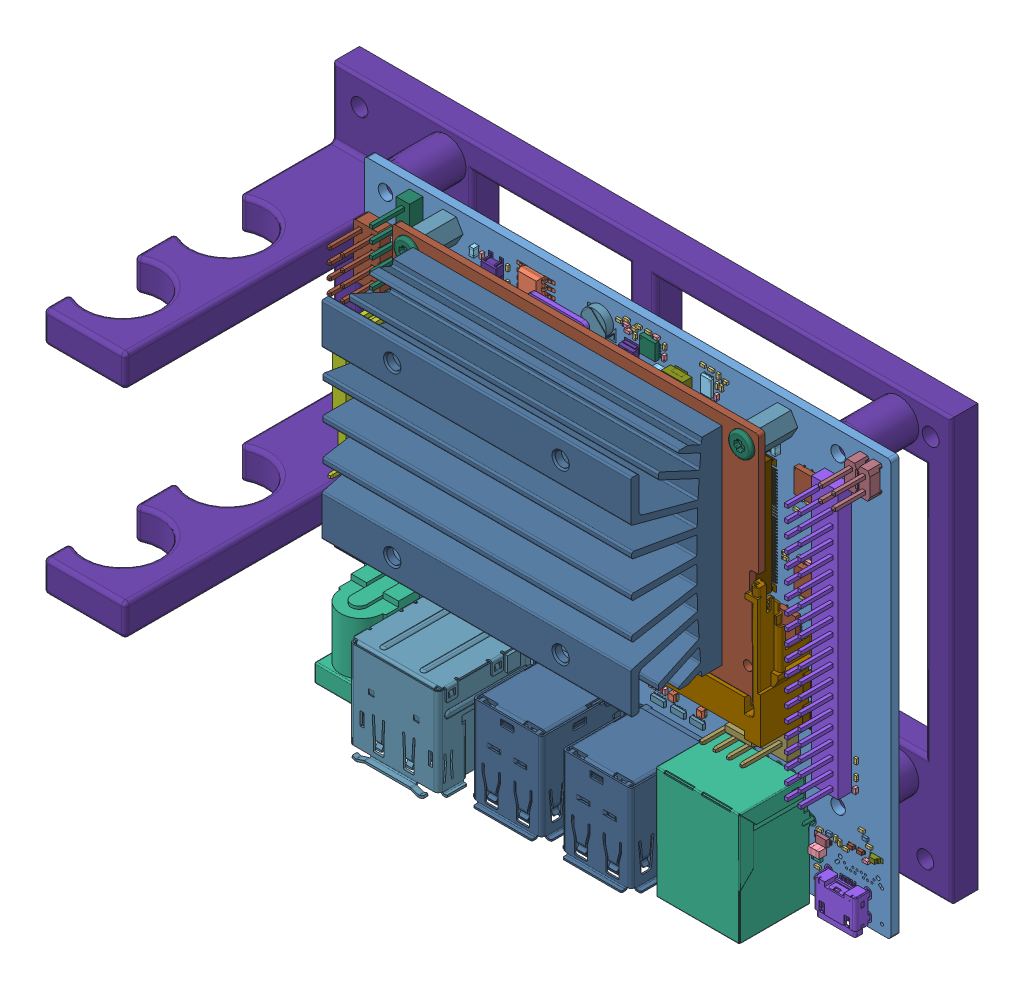
SolidWorks assembly FullJetsonMount, configuration Default. Lengths in mm.
Overall size (117.5 82.03 60).
402 component instances, 71 part files, 3 mates.
Components (placement in the parent):
- Jetson nano_fixed.step-1: Jetson nano_fixed.step [Default] at (-87.2795 66.2016 132.9895) size (100 81.03 30.51)
  - 142-13449-1000-A02_ASM.step-1: 142-13449-1000-A02_ASM.step [Default] at origin size (100 81.03 23.18)
    - 142-13449-1000-A02.step-1: 142-13449-1000-A02.step [Default] at origin size (100 79 1.57)
    - 315-1109-000_1.step-1: 315-1109-000_1.step [Default] at (5.6 4.9 1.575) x (-1 0 0) z (0 0 1) size (4.5 3.5 0.8)
    - 0402_H040.step-1: 0402_H040.step [Default] at (8 -0.825 1.575) size (1 0.5 0.4)
    - 0402_H060.step-1: 0402_H060.step [Default] at (1 5 1.575) x (0 -1 0) z (0 0 1) size (1 0.5 0.6)
    - 0402_H040.step-2: 0402_H040.step [Default] at (9.9 -0.3 1.575) size (1 0.5 0.4)
    - 0402_H040.step-3: 0402_H040.step [Default] at (8.296 51.194 1.575) x (-1 0 0) z (0 0 1) size (1 0.5 0.4)
    - 0402_H040.step-4: 0402_H040.step [Default] at (76.2 36.9 1.575) x (-1 0 0) z (0 0 1) size (1 0.5 0.4)
    - 0402_H040.step-5: 0402_H040.step [Default] at (37.8 2.87 1.575) x (0 -1 0) z (0 0 1) size (1 0.5 0.4)
    - 0402_H040.step-6: 0402_H040.step [Default] at (38.6 2.87 1.575) x (0 -1 0) z (0 0 1) size (1 0.5 0.4)
    - 0402_H060.step-2: 0402_H060.step [Default] at (14.2 7.7 1.575) x (0 -1 0) z (0 0 1) size (1 0.5 0.6)
    - 0402_H040.step-7: 0402_H040.step [Default] at (64 27.5 1.575) x (-1 0 0) z (0 0 1) size (1 0.5 0.4)
    - 0402_H060.step-3: 0402_H060.step [Default] at (18.6 43.15 1.575) x (-1 0 0) z (0 0 1) size (1 0.5 0.6)
    - 0402_H060.step-4: 0402_H060.step [Default] at (65.5 52.8 1.575) x (0 1 0) z (0 0 1) size (1 0.5 0.6)
    - 0402_H060.step-5: 0402_H060.step [Default] at (64 28.4 1.575) x (-1 0 0) z (0 0 1) size (1 0.5 0.6)
    - 0402_H040.step-8: 0402_H040.step [Default] at (60.95 25.85 1.575) size (1 0.5 0.4)
    - 0402_H060.step-6: 0402_H060.step [Default] at (17.3 7.7 1.575) x (0 -1 0) z (0 0 1) size (1 0.5 0.6)
    - 0402_H060.step-7: 0402_H060.step [Default] at (18.6 7.7 1.575) x (0 -1 0) z (0 0 1) size (1 0.5 0.6)
    - 0402_H060.step-8: 0402_H060.step [Default] at (12.9 7.7 1.575) x (0 -1 0) z (0 0 1) size (1 0.5 0.6)
    - 0402_H060.step-9: 0402_H060.step [Default] at (80.9 37.7 1.575) x (-1 0 0) z (0 0 1) size (1 0.5 0.6)
    - 0402_H040.step-9: 0402_H040.step [Default] at (79.5 31.3 1.575) size (1 0.5 0.4)
    - 0402_H040.step-10: 0402_H040.step [Default] at (81 31.3 1.575) x (-1 0 0) z (0 0 1) size (1 0.5 0.4)
    - 0402_H060.step-10: 0402_H060.step [Default] at (79.3 37.7 1.575) size (1 0.5 0.6)
    - 0402_H060.step-11: 0402_H060.step [Default] at (74.8 4.05 1.575) x (-1 0 0) z (0 0 1) size (1 0.5 0.6)
    - 0402_H040.step-11: 0402_H040.step [Default] at (65.675 6.15 1.575) x (0 -1 0) z (0 0 1) size (1 0.5 0.4)
    - 0402_H060.step-12: 0402_H060.step [Default] at (67.7 6.85 1.575) x (0 1 0) z (0 0 1) size (1 0.5 0.6)
    - 0402_H040.step-12: 0402_H040.step [Default] at (64.475 5.8 1.575) x (-1 0 0) z (0 0 1) size (1 0.5 0.4)
    - 0402_H040.step-13: 0402_H040.step [Default] at (67.725 5.325 1.575) x (0 1 0) z (0 0 1) size (1 0.5 0.4)
    - 0402_H060.step-13: 0402_H060.step [Default] at (46.1 59.45 1.575) size (1 0.5 0.6)
    - 0402_H040.step-14: 0402_H040.step [Default] at (44.65 59.45 1.575) size (1 0.5 0.4)
    - 0402_H040.step-15: 0402_H040.step [Default] at (46.1 60.25 1.575) size (1 0.5 0.4)
    - 0402_H060.step-14: 0402_H060.step [Default] at (53.35 57.7 1.575) x (0 -1 0) z (0 0 1) size (1 0.5 0.6)
    - 0402_H040.step-16: 0402_H040.step [Default] at (47.6 59.45 1.575) size (1 0.5 0.4)
    - 0402_H040.step-17: 0402_H040.step [Default] at (48.4 60.25 1.575) size (1 0.5 0.4)
    - 0402_H040.step-18: 0402_H040.step [Default] at (47.7 58.325 1.575) x (0 1 0) z (0 0 1) size (1 0.5 0.4)
    - 0402_H060.step-15: 0402_H060.step [Default] at (46.5 58.65 1.575) x (-1 0 0) z (0 0 1) size (1 0.5 0.6)
    - 0402_H060.step-16: 0402_H060.step [Default] at (51.8 60.25 1.575) size (1 0.5 0.6)
    - 0402_H040.step-19: 0402_H040.step [Default] at (53.35 59.4 1.575) x (0 -1 0) z (0 0 1) size (1 0.5 0.4)
    - 0402_H040.step-20: 0402_H040.step [Default] at (50.2 60.25 1.575) x (-1 0 0) z (0 0 1) size (1 0.5 0.4)
    - 0402_H060.step-17: 0402_H060.step [Default] at (18.6 43.95 1.575) x (-1 0 0) z (0 0 1) size (1 0.5 0.6)
    - 0402_H060.step-18: 0402_H060.step [Default] at (52.75 2.9 1.575) x (0 -1 0) z (0 0 1) size (1 0.5 0.6)
    - 0402_H060.step-19: 0402_H060.step [Default] at (22.35 47.4 1.575) x (-1 0 0) z (0 0 1) size (1 0.5 0.6)
    - 0402_H060.step-20: 0402_H060.step [Default] at (20.55 47.4 1.575) x (-1 0 0) z (0 0 1) size (1 0.5 0.6)
    - 0402_H060.step-21: 0402_H060.step [Default] at (21.95 34.55 1.575) x (0 -1 0) z (0 0 1) size (1 0.5 0.6)
    - 0402_H060.step-22: 0402_H060.step [Default] at (21.05 34.55 1.575) x (0 -1 0) z (0 0 1) size (1 0.5 0.6)
    - 0402_H060.step-23: 0402_H060.step [Default] at (53.55 2.9 1.575) x (0 -1 0) z (0 0 1) size (1 0.5 0.6)
    - 0402_H060.step-24: 0402_H060.step [Default] at (25.4 54 1.575) x (-1 0 0) z (0 0 1) size (1 0.5 0.6)
    - 0402_H060.step-25: 0402_H060.step [Default] at (24 34.58 1.575) x (0 -1 0) z (0 0 1) size (1 0.5 0.6)
    - 0402_H040.step-21: 0402_H040.step [Default] at (55.6 2.95 1.575) x (0 -1 0) z (0 0 1) size (1 0.5 0.4)
    - 0402_H040.step-22: 0402_H040.step [Default] at (20.13 34.53 1.575) x (0 1 0) z (0 0 1) size (1 0.5 0.4)
    - 0402_H060.step-26: 0402_H060.step [Default] at (18.4 35.15 1.575) x (0 1 0) z (0 0 1) size (1 0.5 0.6)
    - 0402_H060.step-27: 0402_H060.step [Default] at (18.4 36.75 1.575) x (0 1 0) z (0 0 1) size (1 0.5 0.6)
    - 0402_H040.step-23: 0402_H040.step [Default] at (39.6 2.87 1.575) x (0 -1 0) z (0 0 1) size (1 0.5 0.4)
    - 0402_H040.step-24: 0402_H040.step [Default] at (40.4 2.87 1.575) x (0 -1 0) z (0 0 1) size (1 0.5 0.4)
    - 0402_H040.step-25: 0402_H040.step [Default] at (60.95 2.95 1.575) x (0 -1 0) z (0 0 1) size (1 0.5 0.4)
    - 0402_H040.step-26: 0402_H040.step [Default] at (60.15 2.95 1.575) x (0 -1 0) z (0 0 1) size (1 0.5 0.4)
    - 0402_H040.step-27: 0402_H040.step [Default] at (54.8 2.95 1.575) x (0 -1 0) z (0 0 1) size (1 0.5 0.4)
    - 0402_H040.step-28: 0402_H040.step [Default] at (31.6 54 1.575) size (1 0.5 0.4)
    - 0402_H040.step-29: 0402_H040.step [Default] at (27.4 54 1.575) size (1 0.5 0.4)
    - 0402_H040.step-30: 0402_H040.step [Default] at (29.6 54 1.575) x (-1 0 0) z (0 0 1) size (1 0.5 0.4)
    - 0402_H040.step-31: 0402_H040.step [Default] at (63.775 -14.475 1.575) size (1 0.5 0.4)
    - 0402_H040.step-32: 0402_H040.step [Default] at (63.775 -15.275 1.575) size (1 0.5 0.4)
    - 0402_H040.step-33: 0402_H040.step [Default] at (8.025 41.475 1.575) x (-1 0 0) z (0 0 1) size (1 0.5 0.4)
    - 0402_H060.step-28: 0402_H060.step [Default] at (63.95 1.25 1.575) x (0 1 0) z (0 0 1) size (1 0.5 0.6)
    - 0402_H060.step-29: 0402_H060.step [Default] at (2.95 54.05 1.575) x (0 1 0) z (0 0 1) size (1 0.5 0.6)
    - 0402_H040.step-34: 0402_H040.step [Default] at (92.2 -3.45 1.575) x (-1 0 0) z (0 0 1) size (1 0.5 0.4)
    - 0402_H060.step-30: 0402_H060.step [Default] at (32.85 7.7 1.575) x (0 -1 0) z (0 0 1) size (1 0.5 0.6)
    - 0402_H060.step-31: 0402_H060.step [Default] at (27.25 7.7 1.575) x (0 -1 0) z (0 0 1) size (1 0.5 0.6)
    - 0402_H060.step-32: 0402_H060.step [Default] at (31.25 7.7 1.575) x (0 -1 0) z (0 0 1) size (1 0.5 0.6)
    - 0402_H060.step-33: 0402_H060.step [Default] at (28.85 7.7 1.575) x (0 -1 0) z (0 0 1) size (1 0.5 0.6)
    - 0402_H060.step-34: 0402_H060.step [Default] at (32.05 7.7 1.575) x (0 -1 0) z (0 0 1) size (1 0.5 0.6)
    - 0402_H060.step-35: 0402_H060.step [Default] at (28.05 7.7 1.575) x (0 -1 0) z (0 0 1) size (1 0.5 0.6)
    - 0402_H060.step-36: 0402_H060.step [Default] at (30.45 7.7 1.575) x (0 -1 0) z (0 0 1) size (1 0.5 0.6)
    - 0402_H060.step-37: 0402_H060.step [Default] at (29.65 7.7 1.575) x (0 -1 0) z (0 0 1) size (1 0.5 0.6)
    - 0402_H060.step-38: 0402_H060.step [Default] at (24.65 6.41 1.575) x (0 -1 0) z (0 0 1) size (1 0.5 0.6)
    - 0402_H060.step-39: 0402_H060.step [Default] at (25.85 6.41 1.575) x (0 -1 0) z (0 0 1) size (1 0.5 0.6)
    - 0402_H060.step-40: 0402_H060.step [Default] at (4.2 36.5 1.575) x (0 1 0) z (0 0 1) size (1 0.5 0.6)
    - 0402_H060.step-41: 0402_H060.step [Default] at (89.7 4.7 1.575) x (0 -1 0) z (0 0 1) size (1 0.5 0.6)
    - 0402_H060.step-42: 0402_H060.step [Default] at (82.5 3.8 1.575) x (0 -1 0) z (0 0 1) size (1 0.5 0.6)
    - 0402_H060.step-43: 0402_H060.step [Default] at (12.65 49.7 1.575) size (1 0.5 0.6)
    - 0402_H060.step-44: 0402_H060.step [Default] at (11.2 50.15 1.575) x (0 -1 0) z (0 0 1) size (1 0.5 0.6)
    - 0402_H060.step-45: 0402_H060.step [Default] at (26.5 34.55 1.575) x (0 -1 0) z (0 0 1) size (1 0.5 0.6)
    - 0402_H060.step-46: 0402_H060.step [Default] at (29.9 34.5 1.575) x (0 -1 0) z (0 0 1) size (1 0.5 0.6)
    - 0402_H060.step-47: 0402_H060.step [Default] at (31.7 40.15 1.575) x (0 1 0) z (0 0 1) size (1 0.5 0.6)
    - 0402_H060.step-48: 0402_H060.step [Default] at (31.15 42.5 1.575) x (0 1 0) z (0 0 1) size (1 0.5 0.6)
    - 0402_H060.step-49: 0402_H060.step [Default] at (19.2 47.05 1.575) x (0 1 0) z (0 0 1) size (1 0.5 0.6)
    - 0402_H060.step-50: 0402_H060.step [Default] at (17.95 42 1.575) x (0 -1 0) z (0 0 1) size (1 0.5 0.6)
    - 0402_H060.step-51: 0402_H060.step [Default] at (27.3 48.25 1.575) x (0 1 0) z (0 0 1) size (1 0.5 0.6)
    - 0402_H060.step-52: 0402_H060.step [Default] at (31.7 37.85 1.575) x (0 -1 0) z (0 0 1) size (1 0.5 0.6)
    - 0402_H060.step-53: 0402_H060.step [Default] at (29.6 48.35 1.575) x (0 1 0) z (0 0 1) size (1 0.5 0.6)
    - 0402_H060.step-54: 0402_H060.step [Default] at (18.8 38.75 1.575) x (-1 0 0) z (0 0 1) size (1 0.5 0.6)
    - 0402_H060.step-55: 0402_H060.step [Default] at (18.7 57.2 1.575) x (0 -1 0) z (0 0 1) size (1 0.5 0.6)
    - 0402_H060.step-56: 0402_H060.step [Default] at (34.1 2.9 1.575) x (0 -1 0) z (0 0 1) size (1 0.5 0.6)
    - 0402_H060.step-57: 0402_H060.step [Default] at (35.8 2.9 1.575) x (0 -1 0) z (0 0 1) size (1 0.5 0.6)
    - 0402_H060.step-58: 0402_H060.step [Default] at (34.9 2.9 1.575) x (0 -1 0) z (0 0 1) size (1 0.5 0.6)
    - 0402_H060.step-59: 0402_H060.step [Default] at (36.6 2.9 1.575) x (0 -1 0) z (0 0 1) size (1 0.5 0.6)
    - 0402_H060.step-60: 0402_H060.step [Default] at (11.325 44.725 1.575) size (1 0.5 0.6)
    - 0402_H060.step-61: 0402_H060.step [Default] at (50.95 2.9 1.575) x (0 -1 0) z (0 0 1) size (1 0.5 0.6)
    - 0402_H060.step-62: 0402_H060.step [Default] at (51.75 2.9 1.575) x (0 -1 0) z (0 0 1) size (1 0.5 0.6)
    - 0402_H060.step-63: 0402_H060.step [Default] at (11.55 39.7 1.575) size (1 0.5 0.6)
    - 0402_H060.step-64: 0402_H060.step [Default] at (9.5 -8.5 1.575) x (-1 0 0) z (0 0 1) size (1 0.5 0.6)
    - 0402_H060.step-65: 0402_H060.step [Default] at (61.35 38.05 1.575) x (0 -1 0) z (0 0 1) size (1 0.5 0.6)
    - 0402_H060.step-66: 0402_H060.step [Default] at (60.55 38.05 1.575) x (0 -1 0) z (0 0 1) size (1 0.5 0.6)
    - 0402_H060.step-67: 0402_H060.step [Default] at (29.3 25.65 1.575) x (0 -1 0) z (0 0 1) size (1 0.5 0.6)
    - 0402_H060.step-68: 0402_H060.step [Default] at (63.3 56.2 1.575) x (0 1 0) z (0 0 1) size (1 0.5 0.6)
    - 0402_H060.step-69: 0402_H060.step [Default] at (20.5 54.2 1.575) size (1 0.5 0.6)
    - 0402_H060.step-70: 0402_H060.step [Default] at (60.1 32.15 1.575) x (0 1 0) z (0 0 1) size (1 0.5 0.6)
    - 0402_H060.step-71: 0402_H060.step [Default] at (60.9 32.15 1.575) x (0 1 0) z (0 0 1) size (1 0.5 0.6)
    - 0402_H060.step-72: 0402_H060.step [Default] at (18.6 44.85 1.575) size (1 0.5 0.6)
    - 0402_H060.step-73: 0402_H060.step [Default] at (18.6 45.65 1.575) size (1 0.5 0.6)
    - 0402_H060.step-74: 0402_H060.step [Default] at (18.1 27.25 1.575) size (1 0.5 0.6)
    - 0402_H060.step-75: 0402_H060.step [Default] at (15.1 7.7 1.575) x (0 -1 0) z (0 0 1) size (1 0.5 0.6)
    - 0402_H060.step-76: 0402_H060.step [Default] at (16.4 7.7 1.575) x (0 -1 0) z (0 0 1) size (1 0.5 0.6)
    - 0402_H060.step-77: 0402_H060.step [Default] at (20.8 7.7 1.575) x (0 -1 0) z (0 0 1) size (1 0.5 0.6)
    - 0402_H060.step-78: 0402_H060.step [Default] at (19.5 7.7 1.575) x (0 -1 0) z (0 0 1) size (1 0.5 0.6)
    - 0402_H060.step-79: 0402_H060.step [Default] at (21.9 2.8 1.575) size (1 0.5 0.6)
    - 0402_H060.step-80: 0402_H060.step [Default] at (12.75 29 1.575) size (1 0.5 0.6)
    - 0402_H060.step-81: 0402_H060.step [Default] at (10.225 5.1 1.575) size (1 0.5 0.6)
    - 0402_H060.step-82: 0402_H060.step [Default] at (22.8 27.65 1.575) x (0 1 0) z (0 0 1) size (1 0.5 0.6)
    - 0402_H060.step-83: 0402_H060.step [Default] at (18.85 25.15 1.575) x (0 -1 0) z (0 0 1) size (1 0.5 0.6)
    - 0402_H060.step-84: 0402_H060.step [Default] at (17.95 40.1 1.575) x (0 1 0) z (0 0 1) size (1 0.5 0.6)
    - 0402_H040.step-35: 0402_H040.step [Default] at (20.8 6.2 1.575) x (0 1 0) z (0 0 1) size (1 0.5 0.4)
    - 0402_H040.step-36: 0402_H040.step [Default] at (76 22.7 1.575) size (1 0.5 0.4)
    - 0402_H040.step-37: 0402_H040.step [Default] at (23.7 26.85 1.575) x (0 1 0) z (0 0 1) size (1 0.5 0.4)
    - 0402_H040.step-38: 0402_H040.step [Default] at (18 25.15 1.575) x (0 1 0) z (0 0 1) size (1 0.5 0.4)
    - 0402_H040.step-39: 0402_H040.step [Default] at (17.3 28.25 1.575) x (-1 0 0) z (0 0 1) size (1 0.5 0.4)
    - 0402_H040.step-40: 0402_H040.step [Default] at (13.15 4.2 1.575) x (0 -1 0) z (0 0 1) size (1 0.5 0.4)
    - 0402_H040.step-41: 0402_H040.step [Default] at (17.2 30.15 1.575) x (0 -1 0) z (0 0 1) size (1 0.5 0.4)
    - 0402_H040.step-42: 0402_H040.step [Default] at (14.2 6.2 1.575) x (0 1 0) z (0 0 1) size (1 0.5 0.4)
    - 0402_H040.step-43: 0402_H040.step [Default] at (12.9 6.2 1.575) x (0 1 0) z (0 0 1) size (1 0.5 0.4)
    - 0402_H040.step-44: 0402_H040.step [Default] at (15.1 6.2 1.575) x (0 1 0) z (0 0 1) size (1 0.5 0.4)
    - 0402_H040.step-45: 0402_H040.step [Default] at (16.4 6.2 1.575) x (0 1 0) z (0 0 1) size (1 0.5 0.4)
    - 0402_H040.step-46: 0402_H040.step [Default] at (19.5 6.2 1.575) x (0 1 0) z (0 0 1) size (1 0.5 0.4)
    - 0402_H040.step-47: 0402_H040.step [Default] at (17.3 6.2 1.575) x (0 1 0) z (0 0 1) size (1 0.5 0.4)
    - 0402_H040.step-48: 0402_H040.step [Default] at (18.6 6.2 1.575) x (0 1 0) z (0 0 1) size (1 0.5 0.4)
    - 0402_H040.step-49: 0402_H040.step [Default] at (24.2 24.55 1.575) x (0 1 0) z (0 0 1) size (1 0.5 0.4)
    - 0402_H040.step-50: 0402_H040.step [Default] at (23.5 54.9 1.575) x (0 1 0) z (0 0 1) size (1 0.5 0.4)
    - 0402_H040.step-51: 0402_H040.step [Default] at (13.2 39.75 1.575) x (-1 0 0) z (0 0 1) size (1 0.5 0.4)
    - 0402_H040.step-52: 0402_H040.step [Default] at (80.7 47.4 1.575) x (-1 0 0) z (0 0 1) size (1 0.5 0.4)
    - 0402_H040.step-53: 0402_H040.step [Default] at (77.5 22.7 1.575) x (-1 0 0) z (0 0 1) size (1 0.5 0.4)
    - 0402_H040.step-54: 0402_H040.step [Default] at (9.25 -12.75 1.575) x (-1 0 0) z (0 0 1) size (1 0.5 0.4)
    - 0402_H040.step-55: 0402_H040.step [Default] at (9.25 -11.95 1.575) x (-1 0 0) z (0 0 1) size (1 0.5 0.4)
    - 0402_H040.step-56: 0402_H040.step [Default] at (64.475 6.7 1.575) size (1 0.5 0.4)
    - 0402_H040.step-57: 0402_H040.step [Default] at (29.3 24 1.575) x (0 1 0) z (0 0 1) size (1 0.5 0.4)
    - 0402_H040.step-58: 0402_H040.step [Default] at (64.2 32.5 1.575) x (0 1 0) z (0 0 1) size (1 0.5 0.4)
    - 0402_H040.step-59: 0402_H040.step [Default] at (64.15 47.45 1.575) x (0 -1 0) z (0 0 1) size (1 0.5 0.4)
    - 0402_H040.step-60: 0402_H040.step [Default] at (64.2 31 1.575) x (0 -1 0) z (0 0 1) size (1 0.5 0.4)
    - 0402_H040.step-61: 0402_H040.step [Default] at (76.2 36.1 1.575) x (-1 0 0) z (0 0 1) size (1 0.5 0.4)
    - 0402_H040.step-62: 0402_H040.step [Default] at (78.4 45.15 1.575) size (1 0.5 0.4)
    - 0402_H040.step-63: 0402_H040.step [Default] at (81.7 38.6 1.575) size (1 0.5 0.4)
    - 0402_H040.step-64: 0402_H040.step [Default] at (81.7 39.4 1.575) size (1 0.5 0.4)
    - 0402_H040.step-65: 0402_H040.step [Default] at (59.35 51.825 1.575) size (1 0.5 0.4)
    - 0402_H040.step-66: 0402_H040.step [Default] at (60.825 51.825 1.575) x (-1 0 0) z (0 0 1) size (1 0.5 0.4)
    - 0402_H040.step-67: 0402_H040.step [Default] at (89.7 9.5 1.575) x (0 1 0) z (0 0 1) size (1 0.5 0.4)
    - 0402_H040.step-68: 0402_H040.step [Default] at (89.7 6.7 1.575) x (0 1 0) z (0 0 1) size (1 0.5 0.4)
    - 0402_H040.step-69: 0402_H040.step [Default] at (3.9 34.2 1.575) x (0 -1 0) z (0 0 1) size (1 0.5 0.4)
    - 0402_H040.step-70: 0402_H040.step [Default] at (5.1 35 1.575) x (0 1 0) z (0 0 1) size (1 0.5 0.4)
    - 0402_H040.step-71: 0402_H040.step [Default] at (32.85 5.81 1.575) x (0 -1 0) z (0 0 1) size (1 0.5 0.4)
    - 0402_H040.step-72: 0402_H040.step [Default] at (32.05 5.81 1.575) x (0 -1 0) z (0 0 1) size (1 0.5 0.4)
    - 0402_H040.step-73: 0402_H040.step [Default] at (27.25 5.81 1.575) x (0 -1 0) z (0 0 1) size (1 0.5 0.4)
    - 0402_H040.step-74: 0402_H040.step [Default] at (28.05 5.81 1.575) x (0 -1 0) z (0 0 1) size (1 0.5 0.4)
    - 0402_H040.step-75: 0402_H040.step [Default] at (31.25 5.81 1.575) x (0 -1 0) z (0 0 1) size (1 0.5 0.4)
    - 0402_H040.step-76: 0402_H040.step [Default] at (30.45 5.81 1.575) x (0 -1 0) z (0 0 1) size (1 0.5 0.4)
    - 0402_H040.step-77: 0402_H040.step [Default] at (28.85 5.81 1.575) x (0 -1 0) z (0 0 1) size (1 0.5 0.4)
    - 0402_H040.step-78: 0402_H040.step [Default] at (29.65 5.81 1.575) x (0 -1 0) z (0 0 1) size (1 0.5 0.4)
    - 0402_H040.step-79: 0402_H040.step [Default] at (13.5 52.9 1.575) x (-1 0 0) z (0 0 1) size (1 0.5 0.4)
    - 0402_H040.step-80: 0402_H040.step [Default] at (22.35 4 1.575) x (0 -1 0) z (0 0 1) size (1 0.5 0.4)
    - 0402_H040.step-81: 0402_H040.step [Default] at (21.55 4 1.575) x (0 1 0) z (0 0 1) size (1 0.5 0.4)
    - 0402_H040.step-82: 0402_H040.step [Default] at (25.85 4.9 1.575) x (0 -1 0) z (0 0 1) size (1 0.5 0.4)
    - 0402_H040.step-83: 0402_H040.step [Default] at (11.8 52.9 1.575) size (1 0.5 0.4)
    - 0402_H040.step-84: 0402_H040.step [Default] at (9.432 51.594 1.575) x (0 -1 0) z (0 0 1) size (1 0.5 0.4)
    - 0402_H040.step-85: 0402_H040.step [Default] at (8.975 50.3 1.575) size (1 0.5 0.4)
    - 0402_H040.step-86: 0402_H040.step [Default] at (82.8 -5.3 1.575) x (-1 0 0) z (0 0 1) size (1 0.5 0.4)
    - 0402_H040.step-87: 0402_H040.step [Default] at (82.4 -11.6 1.575) x (-1 0 0) z (0 0 1) size (1 0.5 0.4)
    - 0402_H040.step-88: 0402_H040.step [Default] at (22.8 26.05 1.575) x (0 1 0) z (0 0 1) size (1 0.5 0.4)
    - 0402_H040.step-89: 0402_H040.step [Default] at (20.8 28.25 1.575) size (1 0.5 0.4)
    - 0402_H040.step-90: 0402_H040.step [Default] at (20.8 24.65 1.575) x (-1 0 0) z (0 0 1) size (1 0.5 0.4)
    - 0402_H040.step-91: 0402_H040.step [Default] at (18.1 26.45 1.575) size (1 0.5 0.4)
    - 0402_H040.step-92: 0402_H040.step [Default] at (24.65 8.41 1.575) x (0 1 0) z (0 0 1) size (1 0.5 0.4)
    - 0402_H040.step-93: 0402_H040.step [Default] at (25.85 8.41 1.575) x (0 1 0) z (0 0 1) size (1 0.5 0.4)
    - 0402_H040.step-94: 0402_H040.step [Default] at (3.8 54.4 1.575) x (0 -1 0) z (0 0 1) size (1 0.5 0.4)
    - 0402_H040.step-95: 0402_H040.step [Default] at (2.45 44.45 1.575) x (0 -1 0) z (0 0 1) size (1 0.5 0.4)
    - 0402_H040.step-96: 0402_H040.step [Default] at (24.65 4.9 1.575) x (0 1 0) z (0 0 1) size (1 0.5 0.4)
    - 0402_H040.step-97: 0402_H040.step [Default] at (22.15 7.6 1.575) x (-1 0 0) z (0 0 1) size (1 0.5 0.4)
    - 0402_H040.step-98: 0402_H040.step [Default] at (79.2 47.4 1.575) size (1 0.5 0.4)
    - 0402_H040.step-99: 0402_H040.step [Default] at (19 28.25 1.575) size (1 0.5 0.4)
    - 0402_H040.step-100: 0402_H040.step [Default] at (9.65 9.7 1.575) x (0 -1 0) z (0 0 1) size (1 0.5 0.4)
    - 0402_H040.step-101: 0402_H040.step [Default] at (28.35 34.45 1.575) x (0 1 0) z (0 0 1) size (1 0.5 0.4)
    - 0402_H040.step-102: 0402_H040.step [Default] at (25.2 34.55 1.575) x (0 1 0) z (0 0 1) size (1 0.5 0.4)
    - 0402_H040.step-103: 0402_H040.step [Default] at (10.625 6.35 1.575) x (0 -1 0) z (0 0 1) size (1 0.5 0.4)
    - 0402_H040.step-104: 0402_H040.step [Default] at (9.825 6.35 1.575) x (0 1 0) z (0 0 1) size (1 0.5 0.4)
    - 0402_H040.step-105: 0402_H040.step [Default] at (4.775 42.975 1.575) x (0 1 0) z (0 0 1) size (1 0.5 0.4)
    - 0402_H040.step-106: 0402_H040.step [Default] at (19.8 32.9 1.575) x (-1 0 0) z (0 0 1) size (1 0.5 0.4)
    - 0402_H040.step-107: 0402_H040.step [Default] at (22.35 24.65 1.575) x (-1 0 0) z (0 0 1) size (1 0.5 0.4)
    - 0402_H040.step-108: 0402_H040.step [Default] at (62.4 54.7 1.575) size (1 0.5 0.4)
    - 0402_H040.step-109: 0402_H040.step [Default] at (62.2 60.05 1.575) x (-1 0 0) z (0 0 1) size (1 0.5 0.4)
    - 0402_H040.step-110: 0402_H040.step [Default] at (23.5 57.5 1.575) x (0 1 0) z (0 0 1) size (1 0.5 0.4)
    - 0402_H040.step-111: 0402_H040.step [Default] at (12.8 44.725 1.575) size (1 0.5 0.4)
    - 0402_H040.step-112: 0402_H040.step [Default] at (21.8 31.45 1.575) x (0 1 0) z (0 0 1) size (1 0.5 0.4)
    - 0402_H040.step-113: 0402_H040.step [Default] at (19.25 34.55 1.575) x (0 1 0) z (0 0 1) size (1 0.5 0.4)
    - 0402_H040.step-114: 0402_H040.step [Default] at (0.95 41.55 1.575) size (1 0.5 0.4)
    - 0402_H040.step-115: 0402_H040.step [Default] at (64.1 58 1.575) x (0 1 0) z (0 0 1) size (1 0.5 0.4)
    - 0402_H040.step-116: 0402_H040.step [Default] at (63.3 58 1.575) x (0 -1 0) z (0 0 1) size (1 0.5 0.4)
    - 0402_H040.step-117: 0402_H040.step [Default] at (63.55 59.7 1.575) x (0 -1 0) z (0 0 1) size (1 0.5 0.4)
    - 0402_H060.step-85: 0402_H060.step [Default] at (71.175 4 1.575) x (-1 0 0) z (0 0 1) size (1 0.5 0.6)
    - 0402_H040.step-118: 0402_H040.step [Default] at (86.6 -5.6 1.575) x (0 1 0) z (0 0 1) size (1 0.5 0.4)
    - 0402_H040.step-119: 0402_H040.step [Default] at (85.8 -5.3 1.575) x (0 1 0) z (0 0 1) size (1 0.5 0.4)
    - 0402_H040.step-120: 0402_H040.step [Default] at (10.25 51.6 1.575) x (0 1 0) z (0 0 1) size (1 0.5 0.4)
    - 0402_H040.step-121: 0402_H040.step [Default] at (80.5 28.55 1.575) size (1 0.5 0.4)
    - 0402_H040.step-122: 0402_H040.step [Default] at (13.95 4.2 1.575) x (0 -1 0) z (0 0 1) size (1 0.5 0.4)
    - 0402_H040.step-123: 0402_H040.step [Default] at (15.35 4.2 1.575) x (0 -1 0) z (0 0 1) size (1 0.5 0.4)
    - 0402_H040.step-124: 0402_H040.step [Default] at (16.15 4.2 1.575) x (0 -1 0) z (0 0 1) size (1 0.5 0.4)
    - 0402_H040.step-125: 0402_H040.step [Default] at (20.55 4.2 1.575) x (0 -1 0) z (0 0 1) size (1 0.5 0.4)
    - 0402_H040.step-126: 0402_H040.step [Default] at (19.75 4.2 1.575) x (0 -1 0) z (0 0 1) size (1 0.5 0.4)
    - 0402_H040.step-127: 0402_H040.step [Default] at (17.6 4.2 1.575) x (0 -1 0) z (0 0 1) size (1 0.5 0.4)
    - 0402_H040.step-128: 0402_H040.step [Default] at (18.4 4.2 1.575) x (0 -1 0) z (0 0 1) size (1 0.5 0.4)
    - 0402_H060.step-86: 0402_H060.step [Default] at (64.25 -13.325 1.575) x (0 -1 0) z (0 0 1) size (1 0.5 0.6)
    - 0402_H060.step-87: 0402_H060.step [Default] at (64.225 -11.825 1.575) x (0 1 0) z (0 0 1) size (1 0.5 0.6)
    - 0402_H040.step-129: 0402_H040.step [Default] at (63.8 -6.85 1.575) x (0 1 0) z (0 0 1) size (1 0.5 0.4)
    - 0402_H040.step-130: 0402_H040.step [Default] at (81.7 41.95 1.575) size (1 0.5 0.4)
    - 0402_H040.step-131: 0402_H040.step [Default] at (87.75 -6 1.575) x (-1 0 0) z (0 0 1) size (1 0.5 0.4)
    - 0402_H040.step-132: 0402_H040.step [Default] at (82.4 -13.6 1.575) x (-1 0 0) z (0 0 1) size (1 0.5 0.4)
    - 0402_H060.step-88: 0402_H060.step [Default] at (91.75 -5.95 1.575) size (1 0.5 0.6)
    - 0402_H040.step-133: 0402_H040.step [Default] at (3.65 49.25 1.575) x (0 -1 0) z (0 0 1) size (1 0.5 0.4)
    - 0402_H040.step-134: 0402_H040.step [Default] at (2.45 49.25 1.575) x (0 1 0) z (0 0 1) size (1 0.5 0.4)
    - 0402_H040.step-135: 0402_H040.step [Default] at (90.75 -1.45 1.575) x (-1 0 0) z (0 0 1) size (1 0.5 0.4)
    - 0402_H040.step-136: 0402_H040.step [Default] at (8.45 39.55 1.575) x (0 -1 0) z (0 0 1) size (1 0.5 0.4)
    - 0402_H060.step-89: 0402_H060.step [Default] at (8.85 -5.25 1.575) x (-1 0 0) z (0 0 1) size (1 0.5 0.6)
    - 0402_H040.step-137: 0402_H040.step [Default] at (18.6 32.55 1.575) x (0 1 0) z (0 0 1) size (1 0.5 0.4)
    - 0402_H060.step-90: 0402_H060.step [Default] at (4.5 44.45 1.575) x (0 1 0) z (0 0 1) size (1 0.5 0.6)
    - 0402_H040.step-138: 0402_H040.step [Default] at (8.35 2.75 1.575) size (1 0.5 0.4)
    - 0402_H040.step-139: 0402_H040.step [Default] at (9.4 1.95 1.575) size (1 0.5 0.4)
    - 0402_H040.step-140: 0402_H040.step [Default] at (8.2 1.55 1.575) x (0 1 0) z (0 0 1) size (1 0.5 0.4)
    - 0402_H060.step-91: 0402_H060.step [Default] at (8.5 3.875 1.575) x (0 -1 0) z (0 0 1) size (1 0.5 0.6)
    - 0402_H060.step-92: 0402_H060.step [Default] at (-0.8 41.5 1.575) x (-1 0 0) z (0 0 1) size (1 0.5 0.6)
    - 0402_H040.step-141: 0402_H040.step [Default] at (-1.35 7.75 1.575) size (1 0.5 0.4)
    - 0402_H040.step-142: 0402_H040.step [Default] at (8 0.425 1.575) size (1 0.5 0.4)
    - 0402_H040.step-143: 0402_H040.step [Default] at (67.9 4.025 1.575) x (-1 0 0) z (0 0 1) size (1 0.5 0.4)
    - 0402_H040.step-144: 0402_H040.step [Default] at (60.6 60.05 1.575) x (-1 0 0) z (0 0 1) size (1 0.5 0.4)
    - 0402_H040.step-145: 0402_H040.step [Default] at (72.85 4 1.575) x (-1 0 0) z (0 0 1) size (1 0.5 0.4)
    - 0402_H040.step-146: 0402_H040.step [Default] at (64.8 59.35 1.575) size (1 0.5 0.4)
    - 0402_H040.step-147: 0402_H040.step [Default] at (7.2 7.3 1.575) size (1 0.5 0.4)
    - 0402_H040.step-148: 0402_H040.step [Default] at (8.5 5.35 1.575) x (0 1 0) z (0 0 1) size (1 0.5 0.4)
    - 0402_H040.step-149: 0402_H040.step [Default] at (8.475 7.075 1.575) x (0 1 0) z (0 0 1) size (1 0.5 0.4)
    - VIRTUAL_SHORT.step-1: VIRTUAL_SHORT.step [Default] at (23.5 32.9 1.575) x (0 1 0) z (0 0 1) size (0.25 0.25 1)
    - VIRTUAL_SHORT.step-2: VIRTUAL_SHORT.step [Default] at (26.85 32.85 1.575) x (0 1 0) z (0 0 1) size (0.25 0.25 1)
    - VIRTUAL_SHORT.step-3: VIRTUAL_SHORT.step [Default] at (30.6 33.8 1.575) x (0 1 0) z (0 0 1) size (0.25 0.25 1)
    - VIRTUAL_SHORT.step-4: VIRTUAL_SHORT.step [Default] at (32.65 39.75 1.575) x (-1 0 0) z (0 0 1) size (0.25 0.25 1)
    - VIRTUAL_SHORT.step-5: VIRTUAL_SHORT.step [Default] at (31.85 42.1 1.575) x (-1 0 0) z (0 0 1) size (0.25 0.25 1)
    - VIRTUAL_SHORT.step-6: VIRTUAL_SHORT.step [Default] at (17.35 42.4 1.575) size (0.25 0.25 1)
    - VIRTUAL_SHORT.step-7: VIRTUAL_SHORT.step [Default] at (18.6 46.6 1.575) size (0.25 0.25 1)
    - VIRTUAL_SHORT.step-8: VIRTUAL_SHORT.step [Default] at (20.9 32.9 1.575) x (0 1 0) z (0 0 1) size (0.25 0.25 1)
    - VIRTUAL_SHORT.step-9: VIRTUAL_SHORT.step [Default] at (28.6 48.25 1.575) x (0 -1 0) z (0 0 1) size (0.25 0.25 1)
    - VIRTUAL_SHORT.step-10: VIRTUAL_SHORT.step [Default] at (27.1 49.35 1.575) x (0 -1 0) z (0 0 1) size (0.25 0.25 1)
    - VIRTUAL_SHORT.step-11: VIRTUAL_SHORT.step [Default] at (22.1 32.95 1.575) x (-1 0 0) z (0 0 1) size (0.25 0.25 1)
    - VIRTUAL_SHORT.step-12: VIRTUAL_SHORT.step [Default] at (32.65 38.25 1.575) x (-1 0 0) z (0 0 1) size (0.25 0.25 1)
    - VIRTUAL_SHORT.step-13: VIRTUAL_SHORT.step [Default] at (30.3 48 1.575) x (-1 0 0) z (0 0 1) size (0.25 0.25 1)
    - VIRTUAL_SHORT.step-14: VIRTUAL_SHORT.step [Default] at (17.15 38.95 1.575) size (0.25 0.25 1)
    - VIRTUAL_SHORT.step-15: VIRTUAL_SHORT.step [Default] at (17.15 39.7 1.575) size (0.25 0.25 1)
    - VIRTUAL_SHORT.step-16: VIRTUAL_SHORT.step [Default] at (76.175 4.1 1.575) x (-1 0 0) z (0 0 1) size (0.25 0.25 1)
    - 064-0377-000_2.step-1: 064-0377-000_2.step [Default] at (2 -4.75 1.575) x (0 -1 0) z (0 0 1) size (14.63 10.08 14.5)
    - 074-0117-000_2.step-1: 074-0117-000_2.step [Default] at (0.254 14.3 1.575) size (5.08 2.54 11.66)
    - 090-0096-000_1.step-1: 090-0096-000_1.step [Default] at (3.45 44.4 1.575) x (0 -1 0) z (0 0 1) size (1.2 0.6 0.4)
    - 090-0309-000_1.step-1: 090-0309-000_1.step [Default] at (-1.65 8.7 1.575) x (-1 0 0) z (0 0 1) size (1.2 0.6 0.4)
    - 115-1232-000_2.step-1: 115-1232-000_2.step [Default] at (1.25 6.5 1.575) x (-1 0 0) z (0 0 1) size (0.9 0.9 0.33)
    - 074-0102-000_4.step-1: 074-0102-000_4.step [Default] at (0.254 44.36 1.575) x (0 1 0) z (0 0 1) size (10.16 5.08 11.6)
    - 064-0400-000_1.step-1: 064-0400-000_1.step [Default] at (73.75 7.77 1.575) size (10.16 5.8 13.5)
    - MEC_STANDOFF_PTH_620C380P.step-1: MEC_STANDOFF_PTH_620C380P.step [Default] at (40.276 40.3 1.575) x (0 1 0) z (0 0 1) size (6.2 6.2 0.73)
    - 090-0231-000_1.step-1: 090-0231-000_1.step [Default] at (35.3 0.7 1.575) x (-1 0 0) z (0 0 1) size (2.5 1.55 0.55)
    - 090-0231-000_1.step-2: 090-0231-000_1.step [Default] at (52.25 0.7 1.575) x (-1 0 0) z (0 0 1) size (2.5 1.55 0.55)
    - 090-0231-000_1.step-3: 090-0231-000_1.step [Default] at (56.05 0.7 1.575) size (2.5 1.55 0.55)
    - 090-0231-000_1.step-4: 090-0231-000_1.step [Default] at (59.65 0.7 1.575) size (2.5 1.55 0.55)
    - 090-0231-000_1.step-5: 090-0231-000_1.step [Default] at (39.1 0.7 1.575) size (2.5 1.55 0.55)
    - 090-0231-000_1.step-6: 090-0231-000_1.step [Default] at (43.1 0.7 1.575) size (2.5 1.55 0.55)
    - 090-0231-000_1.step-7: 090-0231-000_1.step [Default] at (14.6 1.8 1.575) size (2.5 1.55 0.55)
    - 090-0231-000_1.step-8: 090-0231-000_1.step [Default] at (19.1 1.8 1.575) size (2.5 1.55 0.55)
    - 090-0231-000_1.step-9: 090-0231-000_1.step [Default] at (22.5 1.4 1.575) size (2.5 1.55 0.55)
    - 090-0231-000_1.step-10: 090-0231-000_1.step [Default] at (28.45 3.35 1.575) size (2.5 1.55 0.55)
    - 090-0231-000_1.step-11: 090-0231-000_1.step [Default] at (31.65 3.35 1.575) size (2.5 1.55 0.55)
    - 074-0223-000_2.step-1: 074-0223-000_2.step [Default] at (5.85 53.25 1.575) x (0 1 0) z (0 0 1) size (15.24 2.54 11.6)
    - 131-0832-000_2.step-1: 131-0832-000_2.step [Default] at (56.3 54.7 1.575) x (0 -1 0) z (0 0 1) size (4.96 4.06 1.8)
    - 115-0836-000_1.step-1: 115-0836-000_1.step [Default] at (21.1 56.6 1.575) size (2.9 3.58 1.45)
    - 115-0836-000_1.step-2: 115-0836-000_1.step [Default] at (11.8 42.3 1.575) size (2.9 3.58 1.45)
    - 315-0620-000_1.step-1: 315-0620-000_1.step [Default] at (72.1 53.4 1.575) x (0 -1 0) z (0 0 1) size (2.9 3.58 1.1)
    - 315-1062-000_1.step-1: 315-1062-000_1.step [Default] at (26.8 25.15 1.575) x (0 -1 0) z (0 0 1) size (2.9 3.58 1.45)
    - 170-0285-000_1.step-1: 170-0285-000_1.step [Default] at (28.72 57.28 1.575) x (0 1 0) z (0 0 1) size (4.9 7.21 1.75)
    - 115-0138-000_1.step-1: 115-0138-000_1.step [Default] at (9.15 48.55 1.575) x (0 1 0) z (0 0 1) size (2 2.88 1.1)
    - 115-1821-000_1.step-1: 115-1821-000_1.step [Default] at (3.3 40.8 1.575) x (-1 0 0) z (0 0 1) size (2 2.88 1.1)
    - 115-1821-000_1.step-2: 115-1821-000_1.step [Default] at (6.25 39.55 1.575) x (0 -1 0) z (0 0 1) size (2 2.88 1.1)
    - 115-0742-000_2.step-1: 115-0742-000_2.step [Default] at (3.05 46.85 1.575) size (2 2.88 1.1)
    - 115-0742-000_2.step-2: 115-0742-000_2.step [Default] at (3.05 51.65 1.575) x (-1 0 0) z (0 0 1) size (2 2.88 1.1)
    - 115-1821-000_1.step-3: 115-1821-000_1.step [Default] at (59.6 27.6 1.575) x (0 1 0) z (0 0 1) size (2 2.88 1.1)
    - 091-0022-000_1.step-1: 091-0022-000_1.step [Default] at (-0.95 5.7 1.575) size (2 2.51 1.1)
    - 091-0023-000_1.step-1: 091-0023-000_1.step [Default] at (15.25 29.9 1.575) x (0 -1 0) z (0 0 1) size (2 2.51 1.1)
    - 080-1368-000_1.step-1: 080-1368-000_1.step [Default] at (88 -14.3 1.575) size (10.99 7.28 4.95)
    - 080-1656-000_3.step-1: 080-1656-000_3.step [Default] at (44 16.6 1.575) x (-1 0 0) z (0 0 1) size (77.5 25.85 9.76)
    - 090-0243-000_1.step-1: 090-0243-000_1.step [Default] at (8.5 -4.1 1.575) x (-1 0 0) z (0 0 1) size (1.41 0.61 0.45)
    - 090-0243-000_1.step-2: 090-0243-000_1.step [Default] at (9.95 -3.7 1.575) x (0 1 0) z (0 0 1) size (1.41 0.61 0.45)
    - 090-0243-000_1.step-3: 090-0243-000_1.step [Default] at (9.5 -10.95 1.575) x (-1 0 0) z (0 0 1) size (1.41 0.61 0.45)
    - 090-0243-000_1.step-4: 090-0243-000_1.step [Default] at (9.8 -6.25 1.575) x (-1 0 0) z (0 0 1) size (1.41 0.61 0.45)
    - 090-0243-000_1.step-5: 090-0243-000_1.step [Default] at (9.5 -9.5 1.575) x (-1 0 0) z (0 0 1) size (1.41 0.61 0.45)
    - 090-0172-000_1.step-1: 090-0172-000_1.step [Default] at (90.6 -5 1.575) size (1.41 0.61 0.55)
    - 090-0172-000_1.step-2: 090-0172-000_1.step [Default] at (88.8 -5 1.575) x (-1 0 0) z (0 0 1) size (1.41 0.61 0.55)
    - 115-2177-000_2.step-1: 115-2177-000_2.step [Default] at (12.7 51.35 1.575) x (0 1 0) z (0 0 1) size (1.8 1.71 0.4)
    - 090-0233-000_1.step-1: 090-0233-000_1.step [Default] at (83.5 -6.6 1.575) size (3.3 1.3 0.74)
    - 064-0374-000_2.step-1: 064-0374-000_2.step [Default] at (19.75 -9.65 1.575) size (18.1 18.55 21.85)
    - 115-2628-000_3.step-1: 115-2628-000_3.step [Default] at (25.2 41.2 1.575) size (9.5 9.5 0.9)
    - 092-0073-000_1.step-1: 092-0073-000_1.step [Default] at (93.35 -4.75 1.575) x (-1 0 0) z (0 0 1) size (2.46 0.81 0.9)
    - IND_SMD_0402_H060.step-1: IND_SMD_0402_H060.step [Default] at (12.85 29.9 1.575) x (-1 0 0) z (0 0 1) size (1 0.5 0.6)
    - 1206_H190.step-1: 1206_H190.step [Default] at (82 18.8 1.575) x (0 1 0) z (0 0 1) size (3.2 1.6 1.9)
    - 1206_H190.step-2: 1206_H190.step [Default] at (81.95 13.5 1.575) x (0 -1 0) z (0 0 1) size (3.2 1.6 1.9)
    - 300-0868-000_3.step-1: 300-0868-000_3.step [Default] at (69.6 4 1.575) x (-1 0 0) z (0 0 1) size (1 0.6 0.4)
    - 300-0868-000_3.step-2: 300-0868-000_3.step [Default] at (9.55 0.95 1.575) size (1 0.6 0.4)
    - 300-0868-000_3.step-3: 300-0868-000_3.step [Default] at (19.6 31.45 1.575) x (0 -1 0) z (0 0 1) size (1 0.6 0.4)
    - 300-0868-000_3.step-4: 300-0868-000_3.step [Default] at (91.45 -2.45 1.575) x (-1 0 0) z (0 0 1) size (1 0.6 0.4)
    - 300-0868-000_3.step-5: 300-0868-000_3.step [Default] at (84.6 -5.1 1.575) size (1 0.6 0.4)
    - 300-0868-000_3.step-6: 300-0868-000_3.step [Default] at (66.725 5.875 1.575) x (0 -1 0) z (0 0 1) size (1 0.6 0.4)
    - 300-0868-000_3.step-7: 300-0868-000_3.step [Default] at (20.8 31.45 1.575) x (0 -1 0) z (0 0 1) size (1 0.6 0.4)
    - 300-0868-000_3.step-8: 300-0868-000_3.step [Default] at (62.9 31.35 1.575) x (-1 0 0) z (0 0 1) size (1 0.6 0.4)
    - 300-0868-000_3.step-9: 300-0868-000_3.step [Default] at (65.475 4.8 1.575) x (-1 0 0) z (0 0 1) size (1 0.6 0.4)
    - 300-0868-000_3.step-10: 300-0868-000_3.step [Default] at (63.9 33.85 1.575) x (-1 0 0) z (0 0 1) size (1 0.6 0.4)
    - 300-0868-000_3.step-11: 300-0868-000_3.step [Default] at (15.65 27.9 1.575) size (1 0.6 0.4)
    - 300-0868-000_3.step-12: 300-0868-000_3.step [Default] at (11.8 6.1 1.575) x (0 1 0) z (0 0 1) size (1 0.6 0.4)
    - 300-0868-000_3.step-13: 300-0868-000_3.step [Default] at (22.1 6.25 1.575) x (0 1 0) z (0 0 1) size (1 0.6 0.4)
    - 300-0869-000_3.step-1: 300-0869-000_3.step [Default] at (9.65 8.1 1.575) x (0 -1 0) z (0 0 1) size (1 0.6 0.53)
    - 300-0402-000_1.step-1: 300-0402-000_1.step [Default] at (20.8 26.45 1.575) x (0 -1 0) z (0 0 1) size (2 2.69 1.1)
    - 300-0560-000_1.step-1: 300-0560-000_1.step [Default] at (6.8 43.65 1.575) x (-1 0 0) z (0 0 1) size (2 2.69 1.1)
    - 174-0159-000_2.step-1: 174-0159-000_2.step [Default] at (61.49 57.15 1.575) x (-1 0 0) z (0 0 1) size (2 3.52 0.6)
    - 064-0373-000_2.step-1: 064-0373-000_2.step [Default] at (72.95 -7.825 1.575) size (17.8 21.6 17.45)
    - 064-0375-000_2.step-1: 064-0375-000_2.step [Default] at (19.751 -12.275 1.575) size (16.2 5.58 0.01)
    - 074-0221-000_3.step-1: 074-0221-000_3.step [Default] at (86 29 1.575) x (0 1 0) z (0 0 1) size (50.8 5.08 11.6)
    - 2016MM_H100.step-1: 2016MM_H100.step [Default] at (24.5 49.25 1.575) x (0 1 0) z (0 0 1) size (2 1.6 1)
    - 065-0656-000_2.step-1: 065-0656-000_2.step [Default] at (55.6 -10.04 1.575) x (-1 0 0) z (0 0 1) size (16.19 17.45 19.62)
    - 065-0656-000_2.step-2: 065-0656-000_2.step [Default] at (38.6 -10.04 1.575) x (-1 0 0) z (0 0 1) size (16.19 17.45 19.62)
    - 115-1921-000_3.step-1: 115-1921-000_3.step [Default] at (80.45 50.52 1.575) x (0 -1 0) z (0 0 1) size (5 4 1)
    - 115-1921-000_3.step-2: 115-1921-000_3.step [Default] at (80.4 34.5 1.575) x (0 -1 0) z (0 0 1) size (5 4 1)
    - 115-1921-000_3.step-3: 115-1921-000_3.step [Default] at (77.2 25.9 1.575) x (0 -1 0) z (0 0 1) size (5 4 1)
    - 085-0328-000_2.step-1: 085-0328-000_2.step [Default] at (16.28 36.32 1.575) x (0 -1 0) z (0 0 1) size (3.81 2.5 0.6)
    - 074-0216-000_2.step-1: 074-0216-000_2.step [Default] at (92.14 58 1.575) x (-1 0 0) z (0 0 1) size (4.83 5 11.5)
    - 060-0002-000_1.step-1: 060-0002-000_1.step [Default] at (41.2 57.9 1.575) x (0 -1 0) z (0 0 1) size (5.1 5.4 1.68)
    - 316-0697-000_1.step-1: 316-0697-000_1.step [Default] at (50.6 58.1 1.575) x (0 -1 0) z (0 0 1) size (3 3.72 0.8)
    - 032-0256-000_1.step-1: 032-0256-000_1.step [Default] at (5.925 9.425 1.575) size (4.22 2.82 2)
    - 041-0092-000_1.step-1: 041-0092-000_1.step [Default] at (46.9 54.9 1.575) x (0 -1 0) z (0 0 1) size (4.22 2.82 1.2)
    - 080-1243-000_3.step-1: 080-1243-000_3.step [Default] at (69.9 40.3 1.575) x (0 -1 0) z (0 0 1) size (21.9 9.1 4.8)
    - 102-0066-000_2.step-1: 102-0066-000_2.step [Default] at (18 4.2 1.575) size (1 1.86 0.61)
    - 102-0066-000_2.step-2: 102-0066-000_2.step [Default] at (13.55 4.2 1.575) size (1 1.86 0.61)
    - 102-0066-000_2.step-3: 102-0066-000_2.step [Default] at (32.45 5.81 1.575) size (1 1.86 0.61)
    - 102-0066-000_2.step-4: 102-0066-000_2.step [Default] at (27.65 5.81 1.575) size (1 1.86 0.61)
    - 102-0066-000_2.step-5: 102-0066-000_2.step [Default] at (20.15 4.2 1.575) size (1 1.86 0.61)
    - 102-0066-000_2.step-6: 102-0066-000_2.step [Default] at (15.75 4.2 1.575) size (1 1.86 0.61)
    - 102-0066-000_2.step-7: 102-0066-000_2.step [Default] at (29.25 5.81 1.575) size (1 1.86 0.61)
    - 102-0066-000_2.step-8: 102-0066-000_2.step [Default] at (30.85 5.81 1.575) size (1 1.86 0.61)
    - 102-0037-000_1.step-1: 102-0037-000_1.step [Default] at (55.2 2.95 1.575) x (-1 0 0) z (0 0 1) size (1 1.86 0.91)
    - 102-0037-000_1.step-2: 102-0037-000_1.step [Default] at (39.99 2.87 1.575) x (-1 0 0) z (0 0 1) size (1 1.86 0.91)
    - 102-0037-000_1.step-3: 102-0037-000_1.step [Default] at (60.55 2.95 1.575) x (-1 0 0) z (0 0 1) size (1 1.86 0.91)
    - 102-0037-000_1.step-4: 102-0037-000_1.step [Default] at (38.22 2.87 1.575) x (-1 0 0) z (0 0 1) size (1 1.86 0.91)
    - 0805_H140.step-1: 0805_H140.step [Default] at (8.1 -2.1 1.575) size (2.01 1.25 1.4)
    - 0805_H150.step-1: 0805_H150.step [Default] at (82.9 -8.4 1.575) x (-1 0 0) z (0 0 1) size (2.01 1.25 1.5)
    - 0603_H100.step-1: 0603_H100.step [Default] at (6.1 41.525 1.575) x (-1 0 0) z (0 0 1) size (1.6 0.81 1)
    - 0603_H060.step-1: 0603_H060.step [Default] at (63.25 -12 1.575) x (0 1 0) z (0 0 1) size (1.6 0.81 0.6)
    - 0603_H060.step-2: 0603_H060.step [Default] at (63.8 -0.7 1.575) x (0 -1 0) z (0 0 1) size (1.6 0.81 0.6)
    - 0603_H060.step-3: 0603_H060.step [Default] at (82.4 -10 1.575) x (-1 0 0) z (0 0 1) size (1.6 0.81 0.6)
    - 0603_H100.step-2: 0603_H100.step [Default] at (9.486 -7.5 1.575) x (-1 0 0) z (0 0 1) size (1.6 0.81 1)
    - 0603_H100.step-3: 0603_H100.step [Default] at (17.4 57.4 1.575) x (0 -1 0) z (0 0 1) size (1.6 0.81 1)
    - 0603_H100.step-4: 0603_H100.step [Default] at (30.35 25.9 1.575) x (0 -1 0) z (0 0 1) size (1.6 0.81 1)
    - 0603_H100.step-5: 0603_H100.step [Default] at (11.4 45.7 1.575) size (1.6 0.81 1)
    - 0603_H100.step-6: 0603_H100.step [Default] at (3.2 43 1.575) size (1.6 0.81 1)
    - 0603_H100.step-7: 0603_H100.step [Default] at (74.7 53.4 1.575) x (0 -1 0) z (0 0 1) size (1.6 0.81 1)
    - 0603_H100.step-8: 0603_H100.step [Default] at (69.5 53.9 1.575) x (0 -1 0) z (0 0 1) size (1.6 0.81 1)
    - 0603_H100.step-9: 0603_H100.step [Default] at (52.5 52.9 1.575) x (-1 0 0) z (0 0 1) size (1.6 0.81 1)
    - 0603_H100.step-10: 0603_H100.step [Default] at (52.5 54.2 1.575) x (-1 0 0) z (0 0 1) size (1.6 0.81 1)
    - 0603_H100.step-11: 0603_H100.step [Default] at (27.3 51.35 1.575) size (1.6 0.81 1)
    - 0603_H100.step-12: 0603_H100.step [Default] at (22.7 49.1 1.575) x (0 1 0) z (0 0 1) size (1.6 0.81 1)
    - 0603_H100.step-13: 0603_H100.step [Default] at (26.2 48.8 1.575) x (0 1 0) z (0 0 1) size (1.6 0.81 1)
    - 0603_H100.step-14: 0603_H100.step [Default] at (20.9 49.1 1.575) x (0 1 0) z (0 0 1) size (1.6 0.81 1)
    - 0603_H100.step-15: 0603_H100.step [Default] at (65.5 27.4 1.575) x (0 -1 0) z (0 0 1) size (1.6 0.81 1)
    - 0603_H100.step-16: 0603_H100.step [Default] at (63.8 52.2 1.575) x (-1 0 0) z (0 0 1) size (1.6 0.81 1)
    - 0603_H100.step-17: 0603_H100.step [Default] at (52.5 55.4 1.575) x (-1 0 0) z (0 0 1) size (1.6 0.81 1)
    - 080-1669-000_2.step-1: 080-1669-000_2.step [Default] at (0.2 29 1.575) x (0 -1 0) z (0 0 1) size (22.4 5.4 7.7)
  - 244-63448-0000-000_ASM.step-1: 244-63448-0000-000_ASM.step [Default] at (11.2 22.5 8.2712) size (69.6 45 21.37)
    - 142-13448-1000-A02_ASM.step-1: 142-13448-1000-A02_ASM.step [Default] at origin size (23 37.01 4.01)
      - 080-0051-000_3.step-1: 080-0051-000_3.step [Default] at (28.331 29.139 0) x (-1 0 0) z (0 0 -1) size (13.4 17 1.28)
      - TM670M-A2_1.step-1: TM670M-A2_1.step [Default] at (23.7 13.45 1.2) size (23 23 1.29)
    - 142-13448-1000-A02-SKU0000_ASM.step-1: 142-13448-1000-A02-SKU0000_ASM.step [Default] at origin size (23 23 1.29)
      - TM670M-A2_1.step-1: TM670M-A2_1.step [Default] at (23.7 13.45 1.2) size (23 23 1.29)
    - PORG_HSK_ASSY_ASM.step-1: PORG_HSK_ASSY_ASM.step [Default] at (0 0 4.01) size (58.7 39.4 17.3)
      - PORG_HEAT_SINK.step-1: PORG_HEAT_SINK.step [Default] at origin size (58.7 39.4 17.3)
    - 142-63448-1GEN_A00.step-1: 142-63448-1GEN_A00.step [Default] at origin size (69.6 45 1.2)
    - PORG_LEAF_SPRING_DRAWN.step-1: PORG_LEAF_SPRING_DRAWN.step [Default] at (0 0 -0.4) x (1 0.000001 0) z (0 0 1) size (39.83 21.3 1.2)
    - PORG_LEAF_SPRING_SCREW.step-1: PORG_LEAF_SPRING_SCREW.step [Default] at (6.9871 5.9982 5.21) x (0 0 -1) z (0 1 0) size (6.41 4.7 4.7)
    - PORG_LEAF_SPRING_SCREW.step-2: PORG_LEAF_SPRING_SCREW.step [Default] at (6.9871 20.9018 5.21) x (0 0 -1) z (0 1 0) size (6.41 4.7 4.7)
    - PORG_LEAF_SPRING_SCREW.step-3: PORG_LEAF_SPRING_SCREW.step [Default] at (40.4129 20.9018 5.21) x (0 0 -1) z (0 1 0) size (6.41 4.7 4.7)
    - PORG_LEAF_SPRING_SCREW.step-4: PORG_LEAF_SPRING_SCREW.step [Default] at (40.4129 5.9982 5.21) x (0 0 -1) z (0 1 0) size (6.41 4.7 4.7)
  - PORG_HEX_STANDOFF.step-1: PORG_HEX_STANDOFF.step [Default] at (75.8 58.5 8.17) x (-1 0 0) z (0 0 -1) size (5.14 4.45 6.57)
  - PORG_HEX_STANDOFF.step-2: PORG_HEX_STANDOFF.step [Default] at (12.2 58.5 8.17) x (-1 0 0) z (0 0 -1) size (5.14 4.45 6.57)
  - PORG_SYSTEM_SCREW.step-1: PORG_SYSTEM_SCREW.step [Default] at (12.2 58.5 3.73) size (4.55 4.55 4.53)
  - PORG_SYSTEM_SCREW.step-2: PORG_SYSTEM_SCREW.step [Default] at (75.8 58.5 3.73) size (4.55 4.55 4.53)
  - PORG_SYSTEM_SCREW.step-3: PORG_SYSTEM_SCREW.step [Default] at (75.8 58.5 5.67) x (-1 0 0) z (0 0 -1) size (4.55 4.55 4.53)
  - PORG_SYSTEM_SCREW.step-4: PORG_SYSTEM_SCREW.step [Default] at (12.2 58.5 5.67) x (-1 0 0) z (0 0 -1) size (4.55 4.55 4.53)
  - 155-0576-000.step-1: 155-0576-000.step [Default] at (40.276 40.3 5.01) size (5 5 4)
- JetsonMount-2: JetsonMount [Default] at (-111.2791 49.2011 117.9895) x (1 0.000005 0) z (0.000005 -1 0) size (117.5 60 80)
Mates (geometry in assembly coordinates):
- Concentric1: concentric aligned: cylinder of Jetson nano_fixed.step-1/142-13449-1000-A02_ASM.step-1/142-13449-1000-A02.step-1 through (-1.2795 124.2016 132.9895) axis (0 0 1) radius 1.375; cylinder of JetsonMount-2 through (-1.2795 124.2016 112.9895) axis (0 0 1) radius 1.6
- Coincident1: coincident anti-aligned: plane of Jetson nano_fixed.step-1/142-13449-1000-A02_ASM.step-1/142-13449-1000-A02.step-1 through (-87.2795 66.2016 132.9895) normal (0 0 -1); plane of JetsonMount-2 through (-1.2795 124.2016 132.9895) normal (0 0 1)
- Concentric4: concentric aligned: cylinder of Jetson nano_fixed.step-1/142-13449-1000-A02_ASM.step-1/142-13449-1000-A02.step-1 through (-1.2795 66.2016 132.9895) axis (0 0 1) radius 1.375; cylinder of JetsonMount-2 through (-1.2795 66.2016 112.9895) axis (0 0 1) radius 1.6
